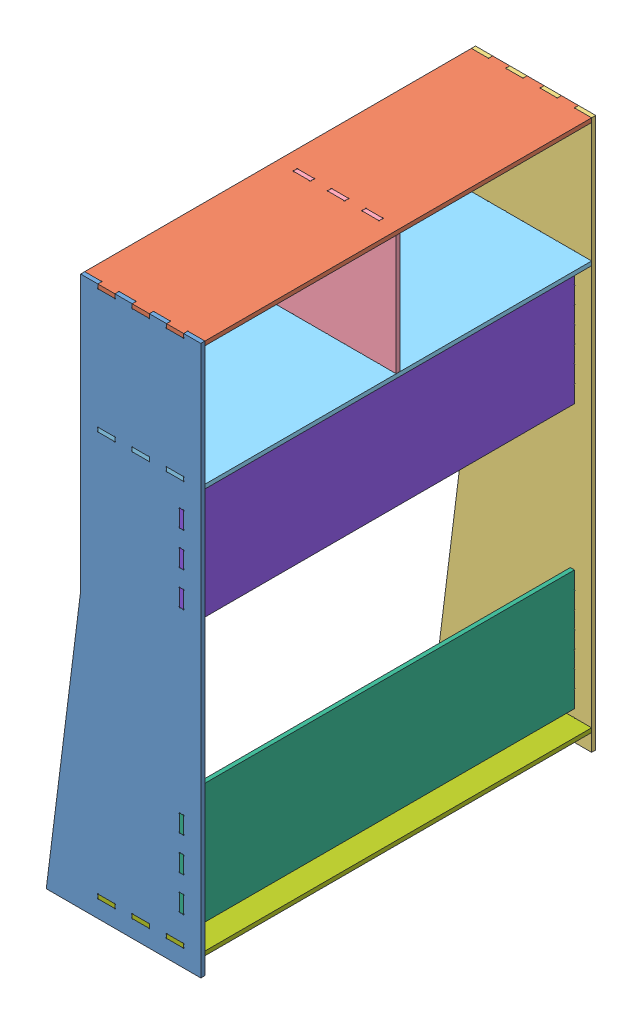
SolidWorks assembly ensamblemuypro, configuration Default. Lengths in mm.
Overall size (450 1600 1149.73).
8 component instances, 8 part files, 18 mates.
Components (placement in the parent):
- basemuypro-1: basemuypro [Default] at (255.3249 386.3271 1414.1302) size (450 1600 12)
- topmuypro-1: topmuypro [Default] at (324.4951 1597.4318 800.2081) x (0 0 -1) z (0 1 0) size (1149.73 350 12)
- basemuypro2-1: basemuypro2 [Default] at (255.3274 386.3271 276.4014) size (450 1600 12)
- encastremypro-1: encastremypro [Default] at (283.509 1422.8053 845.2658) size (349.28 373 12)
- topmuypro2-1: topmuypro2 [Default] at (324.4976 1248.4318 902.3235) x (0 0 1) z (0 -1 0) size (1149.73 350 12)
- botmuypro1-1: botmuypro1 [Default] at (435.5913 255.5868 902.3235) x (0 0 1) z (-1 0 0) size (1149.73 350 12)
- botmuypro2-1: botmuypro2 [Default] at (324.4927 59.4318 800.2081) x (0 0 -1) z (0 1 0) size (1149.73 350 12)
- botmuypro3-1: botmuypro3 [Default] at (435.5913 1024.4641 902.3235) x (0 0 1) z (-1 0 0) size (1149.73 350 12)
Mates (geometry in assembly coordinates):
- Coincident15: coincident anti-aligned: line of basemuypro-1 through (232.3103 1597.4318 1426.1302) axis (-1 0 0); line of topmuypro-1 through (185.5888 1597.4318 1426.1302) axis (1 0 0)
- Coincident23: coincident anti-aligned: plane of topmuypro-1 through (183.8936 1597.4318 286.7051) normal (0 -1 0); plane of basemuypro2-1 through (188.8697 1597.4318 288.4014) normal (0 1 0)
- Coincident24: coincident anti-aligned: line of topmuypro-1 through (188.8673 1609.4318 857.2658) axis (1 0 0); line of encastremypro-1 through (235.5913 1609.4318 857.2658) axis (-1 0 0)
- Coincident30: coincident anti-aligned: line of topmuypro-1 through (285.5913 1609.4318 848.5535) axis (0 0 1); line of encastremypro-1 through (285.5913 1609.4318 857.2658) axis (0 0 -1)
- Coincident32: coincident aligned: line of topmuypro-1 through (182.1958 1609.4318 288.4014) axis (-1 0 0); line of basemuypro2-1 through (185.5913 1609.4318 288.4014) axis (-1 0 0)
- Coincident33: coincident aligned: line of topmuypro-1 through (235.5913 1609.4318 285.0062) axis (0 0 -1); line of basemuypro2-1 through (235.5913 1609.4318 288.4014) axis (0 0 -1)
- Coincident34: coincident anti-aligned: line of basemuypro-1 through (185.5888 1609.4318 1426.1302) axis (0 0 -1); line of topmuypro-1 through (185.5888 1609.4318 1417.5255) axis (0 0 1)
- Coincident57: coincident anti-aligned: line of encastremypro-1 through (185.5913 1236.4318 857.2658) axis (1 0 0); line of topmuypro2-1 through (235.5913 1236.4318 857.2658) axis (-1 0 0)
- Coincident58: coincident anti-aligned: line of encastremypro-1 through (235.5913 1236.4318 857.2658) axis (0 0 -1); line of topmuypro2-1 through (235.5913 1236.4318 845.2658) axis (0 0 1)
- Coincident59: coincident anti-aligned: line of basemuypro2-1 through (435.5913 347.7716 276.4014) axis (0 1 0); line of botmuypro1-1 through (435.5913 394.4931 276.4014) axis (0 -1 0)
- Coincident60: coincident aligned: plane of basemuypro2-1 through (434.3913 1598.6318 276.4014) normal (0 0 -1); plane of botmuypro1-1 through (423.5913 344.4907 276.4014) normal (0 0 -1)
- Coincident61: coincident anti-aligned: line of basemuypro2-1 through (432.3128 394.4931 276.4014) axis (-1 0 0); line of botmuypro1-1 through (423.5913 394.4931 276.4014) axis (1 0 0)
- Coincident62: coincident aligned: line of basemuypro-1 through (388.8659 59.4318 1426.1302) axis (1 0 0); line of botmuypro2-1 through (385.5888 59.4318 1426.1302) axis (1 0 0)
- Coincident63: coincident aligned: plane of basemuypro-1 through (434.3888 1598.6318 1426.1302) normal (0 0 1); plane of botmuypro2-1 through (435.5888 71.4318 1426.1302) normal (0 0 1)
- Coincident64: coincident anti-aligned: line of basemuypro-1 through (435.5888 62.711 1426.1302) axis (0 1 0); line of botmuypro2-1 through (435.5888 71.4318 1426.1302) axis (0 -1 0)
- Coincident75: coincident aligned: line of basemuypro2-1 through (423.5913 1160.0919 276.4014) axis (0 -1 0); line of botmuypro3-1 through (423.5913 1163.3704 276.4014) axis (0 -1 0)
- Coincident76: coincident aligned: plane of basemuypro2-1 through (434.3913 1598.6318 276.4014) normal (0 0 -1); plane of botmuypro3-1 through (423.5913 1113.3679 276.4014) normal (0 0 -1)
- Coincident77: coincident anti-aligned: line of basemuypro2-1 through (432.3128 1163.3704 276.4014) axis (-1 0 0); line of botmuypro3-1 through (423.5913 1163.3704 276.4014) axis (1 0 0)
